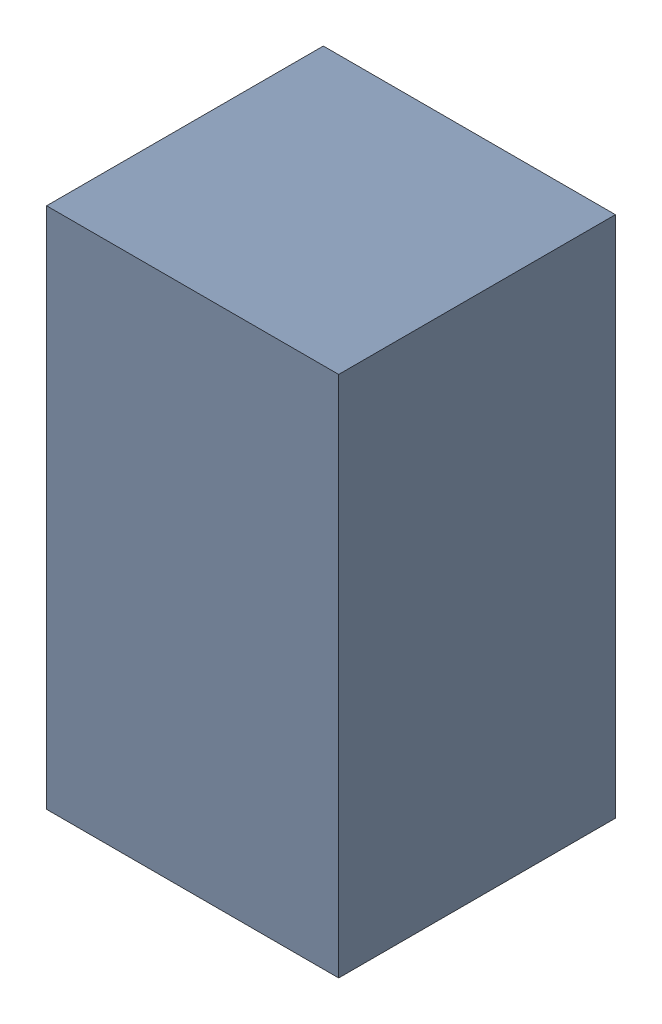
SolidWorks assembly R3_TDA1, configuration Standard. Lengths in mm.
Overall size (0.95 1.7 0.9).
2 component instances, 1 part files, 0 mates.
Components (placement in the parent):
- 885541560-1: 885541560 [Standard] at (4.77 53.29 0) size (0.95 1.7 0.9)
  - Extruded_16-1: Extruded_16 [Standard] at origin size (0.95 1.7 0.9)
